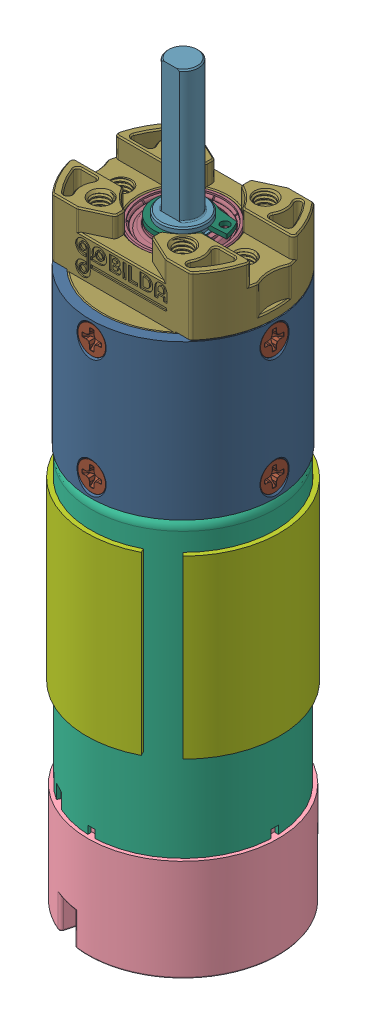
SolidWorks assembly Rex shaft 435rpm motor, configuration Default. Lengths in mm.
Overall size (52.36 142.05 52.36).
38 component instances, 16 part files, 0 mates.
Components (placement in the parent):
- 5202-2402-0014.step-1: 5202-2402-0014.step [Default] at origin size (52.36 142.05 52.36)
  - 5000-0002-0001.step-1: 5000-0002-0001.step [Default] at origin size (52.36 88.75 52.36)
    - 5000-0002-0001 encoder cap.step-1: 5000-0002-0001 encoder cap.step [Default] x (0 1 0) z (0 0 1) size (22.84 52.33 52.33)
      - JST-XH-4POS-VERT (1).step-1: JST-XH-4POS-VERT (1).step [Default] at (2.8 12.25 -75.95) x (1 0 0) z (0 0 -1) size (10.4 12.83 12.83)
        - Plastic (1).step-1: Plastic (1).step [Default] at (-6.1146 -33.6358 -52.1967) x (0 0.707107 0.707107) z (-1 0 0) size (12.4 5.75 7)
        - Pin (1).step-1: Pin (1).step [Default] at (-7.7146 -29.3225 -51.2067) x (0 0.707107 0.707107) z (-1 0 0) size (0.64 0.64 10)
        - Pin (1).step-2: Pin (1).step [Default] at (-7.7146 -34.6258 -56.51) x (0 0.707107 0.707107) z (-1 0 0) size (0.64 0.64 10)
        - Pin (1).step-3: Pin (1).step [Default] at (-7.7146 -32.858 -54.7423) x (0 0.707107 0.707107) z (-1 0 0) size (0.64 0.64 10)
        - Pin (1).step-4: Pin (1).step [Default] at (-7.7146 -31.0902 -52.9745) x (0 0.707107 0.707107) z (-1 0 0) size (0.64 0.64 10)
      - screw.step-1: screw.step [Default] at (-41.264 -8.1646 3.9905) x (0.882398 0 0.470504) z (0 -1 0) size (8.86 7.85 4.95)
        - 99461A915_Phillips Rounded Head Thread-Forming Screws (1).step-1: 99461A915_Phillips Rounded Head Thread-Forming Screws (1).step [Default] at (27.264 -14.6475 -49.347) x (-0.332697 -0.623949 0.707107) z (-0.882398 0.470504 0) size (3.5 3.5 7.4)
      - screw_1.step-1: screw_1.step [Default] at (-14.4172 7.3354 3.9905) x (0.882398 0 0.470504) z (0 -1 0) size (8.86 7.85 4.95)
        - 99461A915_Phillips Rounded Head Thread-Forming Screws (1).step-1: 99461A915_Phillips Rounded Head Thread-Forming Screws (1).step [Default] at (-10.5142 -28.4382 -25.8237) x (-0.332697 -0.623949 0.707107) z (-0.882398 0.470504 0) size (3.5 3.5 7.4)
      - endcap.step-1: endcap.step [Default] at (72.6354 37.1707 -11.0784) x (0 -0.707107 -0.707107) z (1 0 0) size (37 37 21.84)
      - base.step-1: base.step [Default] at (-55.8646 37.1707 -11.0784) x (0 -0.707107 -0.707107) z (-1 0 0) size (34.96 34.31 1)
    - 5000-0002-0001 body.step-1: 5000-0002-0001 body.step [Default] at (-37.1707 3.4854 -11.0784) size (35.61 61.8 35.61)
    - 5000-0002-0001 motor shield.step-1: 5000-0002-0001 motor shield.step [Default] at (-37.1707 54.6354 -11.0784) x (0.808104 0 -0.58904) z (0 -1 0) size (37.5 37.27 34.15)
    - 5000-0002-0001 motor shaft.step-1: 5000-0002-0001 motor shaft.step [Default] at (-37.1707 59.4854 -11.0784) size (3.14 12.45 3.14)
  - 5102-0024-0014.step-1: 5102-0024-0014.step [Default] at origin size (36 67.98 35.98)
    - 5102 Gearbox Base.step-1: 5102 Gearbox Base.step [Default] at (-37.1707 60.1354 -11.0784) size (31.91 5.69 31.91)
    - 5102 Gearbox Barrel (2 stage, simple)_Gear Blank.step-1: 5102 Gearbox Barrel (2 stage, simple)_Gear Blank.step [Default] at (-37.1707 103.1354 -11.0784) x (1 0 0) z (0 -1 0) size (35.98 35.98 30)
    - 5102 Gearbox Barrel Screw (M3 x 8mm length Flat Head)_92010A118.step-1: 5102 Gearbox Barrel Screw (M3 x 8mm length Flat Head)_92010A118.step [Default] at (-37.1707 63.6354 5.0046) x (0.002439 -0.999997 0) z (0 0 1) size (5.46 5.46 8)
    - 5102 Gearbox Face.step-1: 5102 Gearbox Face.step [Default] at (-37.1707 84.6354 -11.0784) size (36 17.1 31.91)
    - 5102 Gearbox Bearing.step-1: 5102 Gearbox Bearing.step [Default] at (-37.1707 92.7354 -11.0784) size (17 5 17)
    - 5102 Gearbox Shaft (23.5mm Length, Simple).step-1: 5102 Gearbox Shaft (23.5mm Length, Simple).step [Default] at (-37.1707 81.2754 -11.0784) x (0.894773 0 -0.44652) z (0.44652 0 0.894773) size (8.97 40.6 8.97)
    - 5102 Gearbox Snap Ring.step-1: 5102 Gearbox Snap Ring.step [Default] at (-37.1707 97.8104 -11.0784) x (0 1 0) z (0 0 1) size (0.85 13.06 10.66)
    - 5102 Gearbox Barrel Screw (M3 x 8mm length Flat Head)_92010A118.step-2: 5102 Gearbox Barrel Screw (M3 x 8mm length Flat Head)_92010A118.step [Default] at (-37.1707 86.6354 5.0046) x (-0.002439 -0.999997 0) z (0 0 1) size (5.46 5.46 8)
    - 5102 Gearbox Barrel Screw (M3 x 8mm length Flat Head)_92010A118.step-3: 5102 Gearbox Barrel Screw (M3 x 8mm length Flat Head)_92010A118.step [Default] at (-21.0877 63.6354 -11.0784) x (0 -0.999997 -0.002439) z (1 0 0) size (5.46 5.46 8)
    - 5102 Gearbox Barrel Screw (M3 x 8mm length Flat Head)_92010A118.step-4: 5102 Gearbox Barrel Screw (M3 x 8mm length Flat Head)_92010A118.step [Default] at (-37.1707 63.6354 -27.1614) x (-0.002439 -0.999997 0) z (0 0 -1) size (5.46 5.46 8)
    - 5102 Gearbox Barrel Screw (M3 x 8mm length Flat Head)_92010A118.step-5: 5102 Gearbox Barrel Screw (M3 x 8mm length Flat Head)_92010A118.step [Default] at (-53.2537 63.6354 -11.0784) x (0 -0.999997 0.002439) z (-1 0 0) size (5.46 5.46 8)
    - 5102 Gearbox Barrel Screw (M3 x 8mm length Flat Head)_92010A118.step-6: 5102 Gearbox Barrel Screw (M3 x 8mm length Flat Head)_92010A118.step [Default] at (-21.0877 86.6354 -11.0784) x (0 -0.999997 0.002439) z (1 0 0) size (5.46 5.46 8)
    - 5102 Gearbox Barrel Screw (M3 x 8mm length Flat Head)_92010A118.step-7: 5102 Gearbox Barrel Screw (M3 x 8mm length Flat Head)_92010A118.step [Default] at (-37.1707 86.6354 -27.1614) x (0.002439 -0.999997 0) z (0 0 -1) size (5.46 5.46 8)
    - 5102 Gearbox Barrel Screw (M3 x 8mm length Flat Head)_92010A118.step-8: 5102 Gearbox Barrel Screw (M3 x 8mm length Flat Head)_92010A118.step [Default] at (-53.2537 86.6354 -11.0784) x (0 -0.999997 -0.002439) z (-1 0 0) size (5.46 5.46 8)
    - 5102 Gearbox Bearing.step-2: 5102 Gearbox Bearing.step [Default] at (-37.1707 84.6354 -11.0784) size (17 5 17)
    - 5102 Gearbox Base Mounting Screw M3 x 5mm length SHCS)_91290A110.step-1: 5102 Gearbox Base Mounting Screw M3 x 5mm length SHCS)_91290A110.step [Default] at (-46.0096 57.2554 -2.2396) x (0.056382 0 0.998409) z (0 -1 0) size (5.5 5.5 8)
    - 5102 Gearbox Base Mounting Screw M3 x 5mm length SHCS)_91290A110.step-2: 5102 Gearbox Base Mounting Screw M3 x 5mm length SHCS)_91290A110.step [Default] at (-28.3319 57.2554 -2.2396) x (0.998409 0 -0.056382) z (0 -1 0) size (5.5 5.5 8)
    - 5102 Gearbox Base Mounting Screw M3 x 5mm length SHCS)_91290A110.step-3: 5102 Gearbox Base Mounting Screw M3 x 5mm length SHCS)_91290A110.step [Default] at (-28.3319 57.2554 -19.9173) x (-0.056382 0 -0.998409) z (0 -1 0) size (5.5 5.5 8)
    - 5102 Gearbox Base Mounting Screw M3 x 5mm length SHCS)_91290A110.step-4: 5102 Gearbox Base Mounting Screw M3 x 5mm length SHCS)_91290A110.step [Default] at (-46.0096 57.2554 -19.9173) x (-0.998409 0 0.056382) z (0 -1 0) size (5.5 5.5 8)
